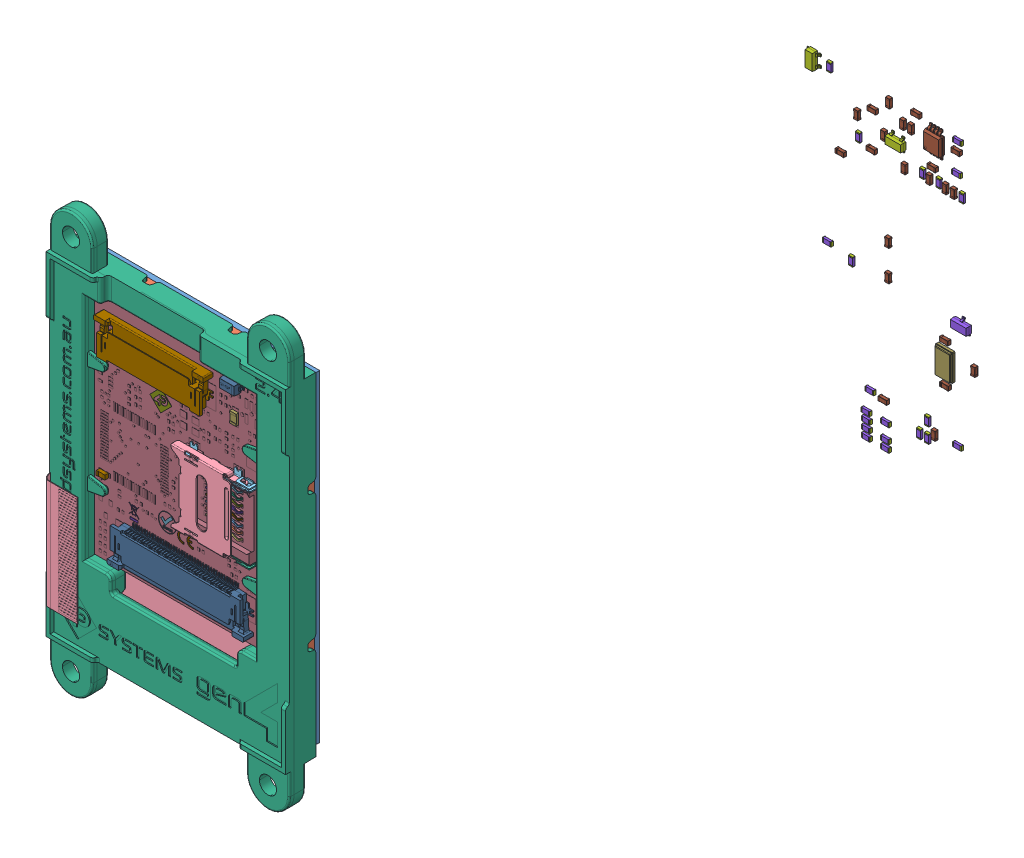
SolidWorks assembly gen4-uLCD-24PT_simplestepmodel_R_1_0, configuration Default. Lengths in mm.
Overall size (171.91 172.67 8.27).
200 component instances, 36 part files, 0 mates.
Components (placement in the parent):
- gen4-uLCD-24PT_simplestepmodel_R_1_0.STEP-1: gen4-uLCD-24PT_simplestepmodel_R_1_0.STEP [Default] at origin size (171.91 172.67 8.27)
  - Assembly-24PT-NoPCB.STEP-1: Assembly-24PT-NoPCB.STEP [Default] at (-2.1876 3.7664 -0.6753) size (44.92 78.36 8.27)
    - 4DLCD-24T-QVGA-LCD.STEP-1: 4DLCD-24T-QVGA-LCD.STEP [Default] at (30.7625 31.8275 58.2815) x (0 1 0) z (0 0 -1) size (60.86 43.86 8.27)
      - 4DLCD-24T-QVGA-GLASS.STEP-1: 4DLCD-24T-QVGA-GLASS.STEP [Default] at (-0.3756 -1.6155 2.7) size (60.26 42.72 1)
      - 4DLCD-24T-QVGA-METAL.STEP-1: 4DLCD-24T-QVGA-METAL.STEP [Default] at (9.2934 0 0) size (60.26 42.72 2.7)
      - 4DLCD-24T-QVGA-LCDGLASS.STEP-1: 4DLCD-24T-QVGA-LCDGLASS.STEP [Default] at (11.9434 0 2.6) size (48.96 36.72 0.1)
      - 4DLCD-24T-QVGA-FLEX.STEP-1: 4DLCD-24T-QVGA-FLEX.STEP [Default] at (-20.8366 -9.4418 -0.1) x (0 -1 0) z (-1 0 0) size (42.86 5.67 25.87)
      - 4DLCD-24T-QVGA-BASE.STEP-1: 4DLCD-24T-QVGA-BASE.STEP [Default] at (9.2934 0 0) size (58.26 40.72 2.7)
    - gen4-24-PT.STEP-1: gen4-24-PT.STEP [Default] at (24.6025 49.8444 58.3015) size (44.83 78.36 5.75)
  - Assembly-PCB-Picaso-REV1.2.STEP-1: Assembly-PCB-Picaso-REV1.2.STEP [Default] at (11.1775 28.3756 26.4775) size (165.23 149.3 2.88)
    - Gen4-PT-REV1.2-PCBComponents.STEP-1: Gen4-PT-REV1.2-PCBComponents.STEP [Default] at (33.2756 -9.2569 32.3517) x (1 0 0) z (0 0 1) size (164.21 147.75 2.22)
      - R4.STEP-1: R4.STEP [Default] at origin size (1.6 0.8 0.46)
        - User_Library-RES_0603L.STEP-1: User_Library-RES_0603L.STEP [Default] at (129.6299 152.3699 0.0127) x (-1 0 0) z (0 1 0) size (1.6 0.46 0.8)
          - User_Library-RES_0603L_RES_0603_Lead_1.STEP-1: User_Library-RES_0603L_RES_0603_Lead_1.STEP [Default] x (-1 0 0) z (0 0 -1) size (0.25 0.45 0.8)
          - User_Library-RES_0603L_RES_0603_Lead_1.STEP-2: User_Library-RES_0603L_RES_0603_Lead_1.STEP [Default] at origin size (0.25 0.45 0.8)
          - User_Library-RES_0603L_RES_0603_Body_1.STEP-1: User_Library-RES_0603L_RES_0603_Body_1.STEP [Default] at origin size (1.5 0.41 0.8)
      - R3.STEP-1: R3.STEP [Default] at origin size (0.8 1.6 0.46)
        - User_Library-RES_0603L.STEP-1: User_Library-RES_0603L.STEP [Default] at (126.2593 149.1969 0.0127) x (0 1 0) z (1 0 0) size (1.6 0.46 0.8)
          - User_Library-RES_0603L_RES_0603_Lead_1.STEP-1: User_Library-RES_0603L_RES_0603_Lead_1.STEP [Default] x (-1 0 0) z (0 0 -1) size (0.25 0.45 0.8)
          - User_Library-RES_0603L_RES_0603_Lead_1.STEP-2: User_Library-RES_0603L_RES_0603_Lead_1.STEP [Default] at origin size (0.25 0.45 0.8)
          - User_Library-RES_0603L_RES_0603_Body_1.STEP-1: User_Library-RES_0603L_RES_0603_Body_1.STEP [Default] at origin size (1.5 0.41 0.8)
      - R25.STEP-1: R25.STEP [Default] at origin size (1.6 0.8 0.46)
        - User_Library-RES_0603L.STEP-1: User_Library-RES_0603L.STEP [Default] at (129.8201 108.3301 0.0127) x (1 0 0) z (0 -1 0) size (1.6 0.46 0.8)
          - User_Library-RES_0603L_RES_0603_Lead_1.STEP-1: User_Library-RES_0603L_RES_0603_Lead_1.STEP [Default] x (-1 0 0) z (0 0 -1) size (0.25 0.45 0.8)
          - User_Library-RES_0603L_RES_0603_Lead_1.STEP-2: User_Library-RES_0603L_RES_0603_Lead_1.STEP [Default] at origin size (0.25 0.45 0.8)
          - User_Library-RES_0603L_RES_0603_Body_1.STEP-1: User_Library-RES_0603L_RES_0603_Body_1.STEP [Default] at origin size (1.5 0.41 0.8)
      - R24.STEP-1: R24.STEP [Default] at origin size (1.6 0.8 0.46)
        - User_Library-RES_0603L.STEP-1: User_Library-RES_0603L.STEP [Default] at (113.4499 109.1249 0.0127) x (-1 0 0) z (0 1 0) size (1.6 0.46 0.8)
          - User_Library-RES_0603L_RES_0603_Lead_1.STEP-1: User_Library-RES_0603L_RES_0603_Lead_1.STEP [Default] x (-1 0 0) z (0 0 -1) size (0.25 0.45 0.8)
          - User_Library-RES_0603L_RES_0603_Lead_1.STEP-2: User_Library-RES_0603L_RES_0603_Lead_1.STEP [Default] at origin size (0.25 0.45 0.8)
          - User_Library-RES_0603L_RES_0603_Body_1.STEP-1: User_Library-RES_0603L_RES_0603_Body_1.STEP [Default] at origin size (1.5 0.41 0.8)
      - R23.STEP-1: R23.STEP [Default] at origin size (0.8 1.6 0.46)
        - User_Library-RES_0603L.STEP-1: User_Library-RES_0603L.STEP [Default] at (124.125 106.8 0.0127) x (0 -1 0) z (-1 0 0) size (1.6 0.46 0.8)
          - User_Library-RES_0603L_RES_0603_Lead_1.STEP-1: User_Library-RES_0603L_RES_0603_Lead_1.STEP [Default] x (-1 0 0) z (0 0 -1) size (0.25 0.45 0.8)
          - User_Library-RES_0603L_RES_0603_Lead_1.STEP-2: User_Library-RES_0603L_RES_0603_Lead_1.STEP [Default] at origin size (0.25 0.45 0.8)
          - User_Library-RES_0603L_RES_0603_Body_1.STEP-1: User_Library-RES_0603L_RES_0603_Body_1.STEP [Default] at origin size (1.5 0.41 0.8)
      - USER_I_O.STEP-1: USER_I_O.STEP [Default] at origin size (20.5 7.15 2.05)
        - Molex-541043031-30Way-Top.STEP-1: Molex-541043031-30Way-Top.STEP [Default] at (-19.6697 44.1643 0) x (-1 0 0) z (0 1 0) size (20.5 2.05 7.15)
      - LCD.STEP-1: LCD.STEP [Default] at origin size (25.5 7.15 2.05)
        - Molex_541044031_-_Top_-_40Way.STEP-1: Molex_541044031_-_Top_-_40Way.STEP [Default] at (-14.6243 18.1077 0) x (1 0 0) z (0 -1 0) size (25.5 2.05 7.15)
      - U1.STEP-1: U1.STEP [Default] at origin size (3.1 4.94 1.1)
        - SW3dPS-MSOP8.STEP-1: SW3dPS-MSOP8.STEP [Default] at (125.8094 155.6968 1.1127) x (0 1 0) z (1 0 0) size (4.94 1.1 3.1)
      - X1.STEP-1: X1.STEP [Default] at origin size (3.2 5 0.85)
        - 628705408.STEP-1: 628705408.STEP [Default] at (127.6519 120.798 0.0127) x (0 1 0) z (0 0 1) size (5 3.2 0.85)
      - uSD1.STEP-1: uSD1.STEP [Default] at origin size (14.4 14.6 2.03)
        - 112C-TXAR-R02_C_1x.STEP-1: 112C-TXAR-R02_C_1x.STEP [Default] at (-7.7099 30.1601 0) x (-1 0 0) z (0 1 0) size (14.4 2.03 14.6)
          - 201-1.STEP-1: 201-1.STEP [Default] at origin size (13.3 1.7 13.1)
          - 301-1.STEP-1: 301-1.STEP [Default] at origin size (8.11 1.32 0.85)
          - 301_1-1.STEP-1: 301_1-1.STEP [Default] at origin size (8.11 1.32 0.85)
          - 301_2-1.STEP-1: 301_2-1.STEP [Default] at origin size (8.11 1.32 0.85)
          - 301_3-1.STEP-1: 301_3-1.STEP [Default] at origin size (8.11 1.32 0.85)
          - 301_4-1.STEP-1: 301_4-1.STEP [Default] at origin size (8.11 1.32 0.85)
          - 301_5-1.STEP-1: 301_5-1.STEP [Default] at origin size (8.11 1.32 0.85)
          - 301_6-1.STEP-1: 301_6-1.STEP [Default] at origin size (8.11 1.32 0.85)
          - 301_7-1.STEP-1: 301_7-1.STEP [Default] at origin size (8.11 1.32 0.85)
          - 401-1.STEP-1: 401-1.STEP [Default] at origin size (13.1 1.85 13.61)
          - 402_L-F-1.STEP-1: 402_L-F-1.STEP [Default] at origin size (12.65 1.73 1.45)
          - 402_R-F-1.STEP-1: 402_R-F-1.STEP [Default] at origin size (12.65 1.73 1.45)
      - U3.STEP-1: U3.STEP [Default] at origin size (2.5 3 1.1)
        - SW3DPS-SOT-23-5-DEFAULT.STEP-1: SW3DPS-SOT-23-5-DEFAULT.STEP [Default] at (102.9447 157.8103 0.5377) x (0 -1 0) z (-1 0 0) size (3 1.1 2.5)
      - U2.STEP-1: U2.STEP [Default] at origin size (3 2.5 1.1)
        - SW3DPS-SOT-23-5-DEFAULT.STEP-1: SW3DPS-SOT-23-5-DEFAULT.STEP [Default] at (118.6397 152.0697 0.5377) x (1 0 0) z (0 -1 0) size (3 1.1 2.5)
      - R22.STEP-1: R22.STEP [Default] at origin size (0.8 1.6 0.46)
        - User_Library-RES_0603L.STEP-1: User_Library-RES_0603L.STEP [Default] at (124.125 109.6 0.0127) x (0 -1 0) z (-1 0 0) size (1.6 0.46 0.8)
          - User_Library-RES_0603L_RES_0603_Lead_1.STEP-1: User_Library-RES_0603L_RES_0603_Lead_1.STEP [Default] x (-1 0 0) z (0 0 -1) size (0.25 0.45 0.8)
          - User_Library-RES_0603L_RES_0603_Lead_1.STEP-2: User_Library-RES_0603L_RES_0603_Lead_1.STEP [Default] at origin size (0.25 0.45 0.8)
          - User_Library-RES_0603L_RES_0603_Body_1.STEP-1: User_Library-RES_0603L_RES_0603_Body_1.STEP [Default] at origin size (1.5 0.41 0.8)
      - R21.STEP-1: R21.STEP [Default] at origin size (1.6 0.8 0.46)
        - User_Library-RES_0603L.STEP-1: User_Library-RES_0603L.STEP [Default] at (116.3001 105.3751 0.0127) x (1 0 0) z (0 -1 0) size (1.6 0.46 0.8)
          - User_Library-RES_0603L_RES_0603_Lead_1.STEP-1: User_Library-RES_0603L_RES_0603_Lead_1.STEP [Default] x (-1 0 0) z (0 0 -1) size (0.25 0.45 0.8)
          - User_Library-RES_0603L_RES_0603_Lead_1.STEP-2: User_Library-RES_0603L_RES_0603_Lead_1.STEP [Default] at origin size (0.25 0.45 0.8)
          - User_Library-RES_0603L_RES_0603_Body_1.STEP-1: User_Library-RES_0603L_RES_0603_Body_1.STEP [Default] at origin size (1.5 0.41 0.8)
      - R20.STEP-1: R20.STEP [Default] at origin size (0.8 1.6 0.46)
        - User_Library-RES_0603L.STEP-1: User_Library-RES_0603L.STEP [Default] at (122.6251 106.7999 0.0127) x (0 -1 0) z (-1 0 0) size (1.6 0.46 0.8)
          - User_Library-RES_0603L_RES_0603_Lead_1.STEP-1: User_Library-RES_0603L_RES_0603_Lead_1.STEP [Default] x (-1 0 0) z (0 0 -1) size (0.25 0.45 0.8)
          - User_Library-RES_0603L_RES_0603_Lead_1.STEP-2: User_Library-RES_0603L_RES_0603_Lead_1.STEP [Default] at origin size (0.25 0.45 0.8)
          - User_Library-RES_0603L_RES_0603_Body_1.STEP-1: User_Library-RES_0603L_RES_0603_Body_1.STEP [Default] at origin size (1.5 0.41 0.8)
      - R19.STEP-1: R19.STEP [Default] at origin size (1.6 0.8 0.46)
        - User_Library-RES_0603L.STEP-1: User_Library-RES_0603L.STEP [Default] at (116.3001 101.2501 0.0127) x (1 0 0) z (0 -1 0) size (1.6 0.46 0.8)
          - User_Library-RES_0603L_RES_0603_Lead_1.STEP-1: User_Library-RES_0603L_RES_0603_Lead_1.STEP [Default] x (-1 0 0) z (0 0 -1) size (0.25 0.45 0.8)
          - User_Library-RES_0603L_RES_0603_Lead_1.STEP-2: User_Library-RES_0603L_RES_0603_Lead_1.STEP [Default] at origin size (0.25 0.45 0.8)
          - User_Library-RES_0603L_RES_0603_Body_1.STEP-1: User_Library-RES_0603L_RES_0603_Body_1.STEP [Default] at origin size (1.5 0.41 0.8)
      - R18.STEP-1: R18.STEP [Default] at origin size (0.8 1.6 0.46)
        - User_Library-RES_0603L.STEP-1: User_Library-RES_0603L.STEP [Default] at (109.9251 128.3999 0.0127) x (0 -1 0) z (-1 0 0) size (1.6 0.46 0.8)
          - User_Library-RES_0603L_RES_0603_Lead_1.STEP-1: User_Library-RES_0603L_RES_0603_Lead_1.STEP [Default] x (-1 0 0) z (0 0 -1) size (0.25 0.45 0.8)
          - User_Library-RES_0603L_RES_0603_Lead_1.STEP-2: User_Library-RES_0603L_RES_0603_Lead_1.STEP [Default] at origin size (0.25 0.45 0.8)
          - User_Library-RES_0603L_RES_0603_Body_1.STEP-1: User_Library-RES_0603L_RES_0603_Body_1.STEP [Default] at origin size (1.5 0.41 0.8)
      - R17.STEP-1: R17.STEP [Default] at origin size (1.6 0.8 0.46)
        - User_Library-RES_0603L.STEP-1: User_Library-RES_0603L.STEP [Default] at (116.3001 102.6251 0.0127) x (1 0 0) z (0 -1 0) size (1.6 0.46 0.8)
          - User_Library-RES_0603L_RES_0603_Lead_1.STEP-1: User_Library-RES_0603L_RES_0603_Lead_1.STEP [Default] x (-1 0 0) z (0 0 -1) size (0.25 0.45 0.8)
          - User_Library-RES_0603L_RES_0603_Lead_1.STEP-2: User_Library-RES_0603L_RES_0603_Lead_1.STEP [Default] at origin size (0.25 0.45 0.8)
          - User_Library-RES_0603L_RES_0603_Body_1.STEP-1: User_Library-RES_0603L_RES_0603_Body_1.STEP [Default] at origin size (1.5 0.41 0.8)
      - R16.STEP-1: R16.STEP [Default] at origin size (1.6 0.8 0.46)
        - User_Library-RES_0603L.STEP-1: User_Library-RES_0603L.STEP [Default] at (112.7251 101.2501 0.0127) x (1 0 0) z (0 -1 0) size (1.6 0.46 0.8)
          - User_Library-RES_0603L_RES_0603_Lead_1.STEP-1: User_Library-RES_0603L_RES_0603_Lead_1.STEP [Default] x (-1 0 0) z (0 0 -1) size (0.25 0.45 0.8)
          - User_Library-RES_0603L_RES_0603_Lead_1.STEP-2: User_Library-RES_0603L_RES_0603_Lead_1.STEP [Default] at origin size (0.25 0.45 0.8)
          - User_Library-RES_0603L_RES_0603_Body_1.STEP-1: User_Library-RES_0603L_RES_0603_Body_1.STEP [Default] at origin size (1.5 0.41 0.8)
      - R15.STEP-1: R15.STEP [Default] at origin size (1.6 0.8 0.46)
        - User_Library-RES_0603L.STEP-1: User_Library-RES_0603L.STEP [Default] at (112.7251 102.6251 0.0127) x (1 0 0) z (0 -1 0) size (1.6 0.46 0.8)
          - User_Library-RES_0603L_RES_0603_Lead_1.STEP-1: User_Library-RES_0603L_RES_0603_Lead_1.STEP [Default] x (-1 0 0) z (0 0 -1) size (0.25 0.45 0.8)
          - User_Library-RES_0603L_RES_0603_Lead_1.STEP-2: User_Library-RES_0603L_RES_0603_Lead_1.STEP [Default] at origin size (0.25 0.45 0.8)
          - User_Library-RES_0603L_RES_0603_Body_1.STEP-1: User_Library-RES_0603L_RES_0603_Body_1.STEP [Default] at origin size (1.5 0.41 0.8)
      - R14.STEP-1: R14.STEP [Default] at origin size (1.6 0.8 0.46)
        - User_Library-RES_0603L.STEP-1: User_Library-RES_0603L.STEP [Default] at (112.7251 104.0001 0.0127) x (1 0 0) z (0 -1 0) size (1.6 0.46 0.8)
          - User_Library-RES_0603L_RES_0603_Lead_1.STEP-1: User_Library-RES_0603L_RES_0603_Lead_1.STEP [Default] x (-1 0 0) z (0 0 -1) size (0.25 0.45 0.8)
          - User_Library-RES_0603L_RES_0603_Lead_1.STEP-2: User_Library-RES_0603L_RES_0603_Lead_1.STEP [Default] at origin size (0.25 0.45 0.8)
          - User_Library-RES_0603L_RES_0603_Body_1.STEP-1: User_Library-RES_0603L_RES_0603_Body_1.STEP [Default] at origin size (1.5 0.41 0.8)
      - R13.STEP-1: R13.STEP [Default] at origin size (1.6 0.8 0.46)
        - User_Library-RES_0603L.STEP-1: User_Library-RES_0603L.STEP [Default] at (112.7001 105.3751 0.0127) x (1 0 0) z (0 -1 0) size (1.6 0.46 0.8)
          - User_Library-RES_0603L_RES_0603_Lead_1.STEP-1: User_Library-RES_0603L_RES_0603_Lead_1.STEP [Default] x (-1 0 0) z (0 0 -1) size (0.25 0.45 0.8)
          - User_Library-RES_0603L_RES_0603_Lead_1.STEP-2: User_Library-RES_0603L_RES_0603_Lead_1.STEP [Default] at origin size (0.25 0.45 0.8)
          - User_Library-RES_0603L_RES_0603_Body_1.STEP-1: User_Library-RES_0603L_RES_0603_Body_1.STEP [Default] at origin size (1.5 0.41 0.8)
      - R12.STEP-1: R12.STEP [Default] at origin size (1.6 0.8 0.46)
        - User_Library-RES_0603L.STEP-1: User_Library-RES_0603L.STEP [Default] at (105.4601 129.2201 0.0127) x (1 0 0) z (0 -1 0) size (1.6 0.46 0.8)
          - User_Library-RES_0603L_RES_0603_Lead_1.STEP-1: User_Library-RES_0603L_RES_0603_Lead_1.STEP [Default] x (-1 0 0) z (0 0 -1) size (0.25 0.45 0.8)
          - User_Library-RES_0603L_RES_0603_Lead_1.STEP-2: User_Library-RES_0603L_RES_0603_Lead_1.STEP [Default] at origin size (0.25 0.45 0.8)
          - User_Library-RES_0603L_RES_0603_Body_1.STEP-1: User_Library-RES_0603L_RES_0603_Body_1.STEP [Default] at origin size (1.5 0.41 0.8)
      - R11.STEP-1: R11.STEP [Default] at origin size (0.8 1.6 0.46)
        - User_Library-RES_0603L.STEP-1: User_Library-RES_0603L.STEP [Default] at (130.8199 149.1901 0.2277) x (0 1 0) z (1 0 0) size (1.6 0.46 0.8)
          - User_Library-RES_0603L_RES_0603_Lead_1.STEP-1: User_Library-RES_0603L_RES_0603_Lead_1.STEP [Default] x (-1 0 0) z (0 0 -1) size (0.25 0.45 0.8)
          - User_Library-RES_0603L_RES_0603_Lead_1.STEP-2: User_Library-RES_0603L_RES_0603_Lead_1.STEP [Default] at origin size (0.25 0.45 0.8)
          - User_Library-RES_0603L_RES_0603_Body_1.STEP-1: User_Library-RES_0603L_RES_0603_Body_1.STEP [Default] at origin size (1.5 0.41 0.8)
      - R10.STEP-1: R10.STEP [Default] at origin size (0.8 1.6 0.46)
        - User_Library-RES_0603L.STEP-1: User_Library-RES_0603L.STEP [Default] at (105.8251 157.7749 0.0127) x (0 -1 0) z (-1 0 0) size (1.6 0.46 0.8)
          - User_Library-RES_0603L_RES_0603_Lead_1.STEP-1: User_Library-RES_0603L_RES_0603_Lead_1.STEP [Default] x (-1 0 0) z (0 0 -1) size (0.25 0.45 0.8)
          - User_Library-RES_0603L_RES_0603_Lead_1.STEP-2: User_Library-RES_0603L_RES_0603_Lead_1.STEP [Default] at origin size (0.25 0.45 0.8)
          - User_Library-RES_0603L_RES_0603_Body_1.STEP-1: User_Library-RES_0603L_RES_0603_Body_1.STEP [Default] at origin size (1.5 0.41 0.8)
      - R6.STEP-1: R6.STEP [Default] at origin size (0.8 1.6 0.46)
        - User_Library-RES_0603L.STEP-1: User_Library-RES_0603L.STEP [Default] at (111.2301 149.1199 0.0127) x (0 -1 0) z (-1 0 0) size (1.6 0.46 0.8)
          - User_Library-RES_0603L_RES_0603_Lead_1.STEP-1: User_Library-RES_0603L_RES_0603_Lead_1.STEP [Default] x (-1 0 0) z (0 0 -1) size (0.25 0.45 0.8)
          - User_Library-RES_0603L_RES_0603_Lead_1.STEP-2: User_Library-RES_0603L_RES_0603_Lead_1.STEP [Default] at origin size (0.25 0.45 0.8)
          - User_Library-RES_0603L_RES_0603_Body_1.STEP-1: User_Library-RES_0603L_RES_0603_Body_1.STEP [Default] at origin size (1.5 0.41 0.8)
      - R2.STEP-1: R2.STEP [Default] at origin size (0.8 1.6 0.46)
        - User_Library-RES_0603L.STEP-1: User_Library-RES_0603L.STEP [Default] at (123.2095 149.2217 0.0127) x (0 -1 0) z (-1 0 0) size (1.6 0.46 0.8)
          - User_Library-RES_0603L_RES_0603_Lead_1.STEP-1: User_Library-RES_0603L_RES_0603_Lead_1.STEP [Default] x (-1 0 0) z (0 0 -1) size (0.25 0.45 0.8)
          - User_Library-RES_0603L_RES_0603_Lead_1.STEP-2: User_Library-RES_0603L_RES_0603_Lead_1.STEP [Default] at origin size (0.25 0.45 0.8)
          - User_Library-RES_0603L_RES_0603_Body_1.STEP-1: User_Library-RES_0603L_RES_0603_Body_1.STEP [Default] at origin size (1.5 0.41 0.8)
      - R1.STEP-1: R1.STEP [Default] at origin size (1.6 0.8 0.46)
        - User_Library-RES_0603L.STEP-1: User_Library-RES_0603L.STEP [Default] at (129.8093 157.6717 0.0127) x (-1 0 0) z (0 1 0) size (1.6 0.46 0.8)
          - User_Library-RES_0603L_RES_0603_Lead_1.STEP-1: User_Library-RES_0603L_RES_0603_Lead_1.STEP [Default] x (-1 0 0) z (0 0 -1) size (0.25 0.45 0.8)
          - User_Library-RES_0603L_RES_0603_Lead_1.STEP-2: User_Library-RES_0603L_RES_0603_Lead_1.STEP [Default] at origin size (0.25 0.45 0.8)
          - User_Library-RES_0603L_RES_0603_Body_1.STEP-1: User_Library-RES_0603L_RES_0603_Body_1.STEP [Default] at origin size (1.5 0.41 0.8)
      - Q1.STEP-1: Q1.STEP [Default] at origin size (3 2.5 1.1)
        - SW3DPS-SOT-23-DEFAULT.STEP-1: SW3DPS-SOT-23-DEFAULT.STEP [Default] at (130.8699 128.4699 0.5127) x (-1 0 0) z (0 1 0) size (3 1.1 2.5)
      - L1.STEP-1: L1.STEP [Default] at origin size (1.6 0.8 0.7)
        - User_Library-ECHU_PPS.STEP-1: User_Library-ECHU_PPS.STEP [Default] at (-29.8699 24.0601 0) x (1 0 0) z (0 0 1) size (1.6 0.8 0.7)
      - D1.STEP-1: D1.STEP [Default] at origin size (3.85 1.71 1.45)
        - User_Library-SOD-123_DiodesInc.STEP-1: User_Library-SOD-123_DiodesInc.STEP [Default] at (-4.125 51.69 0.5) x (-1 0 0) z (0 0 1) size (3.85 1.7 1.45)
      - C23.STEP-1: C23.STEP [Default] at origin size (1.6 0.8 0.6)
        - User_Library-cap_0603_lowprofile.STEP-1: User_Library-cap_0603_lowprofile.STEP [Default] at (114.1499 155.0999 0.0127) x (-1 0 0) z (0 0 1) size (1.6 0.8 0.6)
      - C22.STEP-1: C22.STEP [Default] at origin size (0.8 1.6 0.6)
        - User_Library-cap_0603_lowprofile.STEP-1: User_Library-cap_0603_lowprofile.STEP [Default] at (111.2301 152.9099 0.0127) x (0 -1 0) z (0 0 1) size (1.6 0.8 0.6)
      - C21.STEP-1: C21.STEP [Default] at origin size (1.6 0.8 0.6)
        - User_Library-cap_0603_lowprofile.STEP-1: User_Library-cap_0603_lowprofile.STEP [Default] at (108.1901 145.2201 0.0127) size (1.6 0.8 0.6)
      - C20.STEP-1: C20.STEP [Default] at origin size (0.8 1.6 0.6)
        - User_Library-cap_0603_lowprofile.STEP-1: User_Library-cap_0603_lowprofile.STEP [Default] at (125.7 108.25 0.0127) x (0 -1 0) z (0 0 1) size (1.6 0.8 0.6)
      - C19.STEP-1: C19.STEP [Default] at origin size (1.6 0.8 0.6)
        - User_Library-cap_0603_lowprofile.STEP-1: User_Library-cap_0603_lowprofile.STEP [Default] at (116.2251 109.1251 0.0127) size (1.6 0.8 0.6)
      - C18.STEP-1: C18.STEP [Default] at origin size (0.8 1.6 0.6)
        - User_Library-cap_0603_lowprofile.STEP-1: User_Library-cap_0603_lowprofile.STEP [Default] at (119.8094 155.6219 0.0127) x (0 1 0) z (0 0 1) size (1.6 0.8 0.6)
      - C17.STEP-1: C17.STEP [Default] at origin size (0.8 1.6 0.6)
        - User_Library-cap_0603_lowprofile.STEP-1: User_Library-cap_0603_lowprofile.STEP [Default] at (117.0499 129.4251 0.0127) x (0 1 0) z (0 0 1) size (1.6 0.8 0.6)
      - C16.STEP-1: C16.STEP [Default] at origin size (1.6 0.8 0.6)
        - User_Library-cap_0603_lowprofile.STEP-1: User_Library-cap_0603_lowprofile.STEP [Default] at (127.7501 117.2001 0.0127) size (1.6 0.8 0.6)
      - C15.STEP-1: C15.STEP [Default] at origin size (1.6 0.8 0.6)
        - User_Library-cap_0603_lowprofile.STEP-1: User_Library-cap_0603_lowprofile.STEP [Default] at (127.6749 124.4749 0.0127) x (-1 0 0) z (0 0 1) size (1.6 0.8 0.6)
      - C14.STEP-1: C14.STEP [Default] at origin size (0.8 1.6 0.6)
        - User_Library-cap_0603_lowprofile.STEP-1: User_Library-cap_0603_lowprofile.STEP [Default] at (117.0499 135.1601 0.0127) x (0 1 0) z (0 0 1) size (1.6 0.8 0.6)
      - C12.STEP-1: C12.STEP [Default] at origin size (0.8 1.6 0.6)
        - User_Library-cap_0603_lowprofile.STEP-1: User_Library-cap_0603_lowprofile.STEP [Default] at (121.2999 155.6251 0.0127) x (0 1 0) z (0 0 1) size (1.6 0.8 0.6)
      - C11.STEP-1: C11.STEP [Default] at origin size (0.8 1.6 0.6)
        - User_Library-cap_0603_lowprofile.STEP-1: User_Library-cap_0603_lowprofile.STEP [Default] at (133.1399 122.3101 0.0127) x (0 1 0) z (0 0 1) size (1.6 0.8 0.6)
      - C10.STEP-1: C10.STEP [Default] at origin size (0.8 1.6 0.6)
        - User_Library-cap_0603_lowprofile.STEP-1: User_Library-cap_0603_lowprofile.STEP [Default] at (117.1751 157.7999 0.0127) x (0 -1 0) z (0 0 1) size (1.6 0.8 0.6)
      - C9.STEP-1: C9.STEP [Default] at origin size (0.8 1.6 0.6)
        - User_Library-cap_0603_lowprofile.STEP-1: User_Library-cap_0603_lowprofile.STEP [Default] at (120.0749 148.6001 0.0127) x (0 1 0) z (0 0 1) size (1.6 0.8 0.6)
      - C8.STEP-1: C8.STEP [Default] at origin size (0.8 1.6 0.6)
        - User_Library-cap_0603_lowprofile.STEP-1: User_Library-cap_0603_lowprofile.STEP [Default] at (116.2501 152.0499 0.0127) x (0 -1 0) z (0 0 1) size (1.6 0.8 0.6)
      - C7.STEP-1: C7.STEP [Default] at origin size (1.6 0.8 0.6)
        - User_Library-cap_0603_lowprofile.STEP-1: User_Library-cap_0603_lowprofile.STEP [Default] at (113.9801 148.5501 0.0127) size (1.6 0.8 0.6)
      - C6.STEP-1: C6.STEP [Default] at origin size (1.6 0.8 0.6)
        - User_Library-cap_0603_lowprofile.STEP-1: User_Library-cap_0603_lowprofile.STEP [Default] at (125.3251 151.3251 0.0127) size (1.6 0.8 0.6)
      - C5.STEP-1: C5.STEP [Default] at origin size (1.6 0.8 0.6)
        - User_Library-cap_0603_lowprofile.STEP-1: User_Library-cap_0603_lowprofile.STEP [Default] at (129.8093 156.1967 0.0127) x (-1 0 0) z (0 0 1) size (1.6 0.8 0.6)
      - C4.STEP-1: C4.STEP [Default] at origin size (0.8 1.6 0.6)
        - User_Library-cap_0603_lowprofile.STEP-1: User_Library-cap_0603_lowprofile.STEP [Default] at (129.2845 149.1967 0.0127) x (0 -1 0) z (0 0 1) size (1.6 0.8 0.6)
      - C3.STEP-1: C3.STEP [Default] at origin size (0.8 1.6 0.6)
        - User_Library-cap_0603_lowprofile.STEP-1: User_Library-cap_0603_lowprofile.STEP [Default] at (127.7594 149.1969 0.0127) x (0 1 0) z (0 0 1) size (1.6 0.8 0.6)
      - C2.STEP-1: C2.STEP [Default] at origin size (0.8 1.6 0.6)
        - User_Library-cap_0603_lowprofile.STEP-1: User_Library-cap_0603_lowprofile.STEP [Default] at (124.7345 149.1967 0.0127) x (0 -1 0) z (0 0 1) size (1.6 0.8 0.6)
      - C1.STEP-1: C1.STEP [Default] at origin size (1.6 0.8 0.6)
        - User_Library-cap_0603_lowprofile.STEP-1: User_Library-cap_0603_lowprofile.STEP [Default] at (122.3001 158.5001 0.0127) size (1.6 0.8 0.6)
      - L4.STEP-1: L4.STEP [Default] at origin size (1.2 2 0.5)
        - 0805-Inductor.STEP-1: 0805-Inductor.STEP [Default] at (-4.7299 44.2281 0.35) x (0 1 0) z (0 0 1) size (2 1.2 0.5)
    - Gen4-PT-REV1.2OutLine.STEP-1: Gen4-PT-REV1.2OutLine.STEP [Default] at (33.2836 -9.2486 32.3147) size (31.7 42.5 0.87)
    - RoHS2.STEP-1: RoHS2.STEP [Default] at (13.5916 10.9296 32.3507) x (0.999982 -0.005956 0) z (0 0 -1) size (3.32 3.32 0.04)
    - SD-Logo.STEP-1: SD-Logo.STEP [Default] at (18.0324 18.573 32.3507) x (0.023632 -0.999721 0) z (0 0 1) size (3.32 1.09 0.04)
    - 4D-Logo.STEP-1: 4D-Logo.STEP [Default] at (11.7637 29.6556 32.3507) size (4.06 4.06 0.05)
    - Bin.STEP-1: Bin.STEP [Default] at (8.9799 11.1717 32.3507) size (1.92 2.67 0.05)
    - CE.STEP-1: CE.STEP [Default] at (17.1637 10.7288 32.3507) size (2.89 2.06 0.05)
